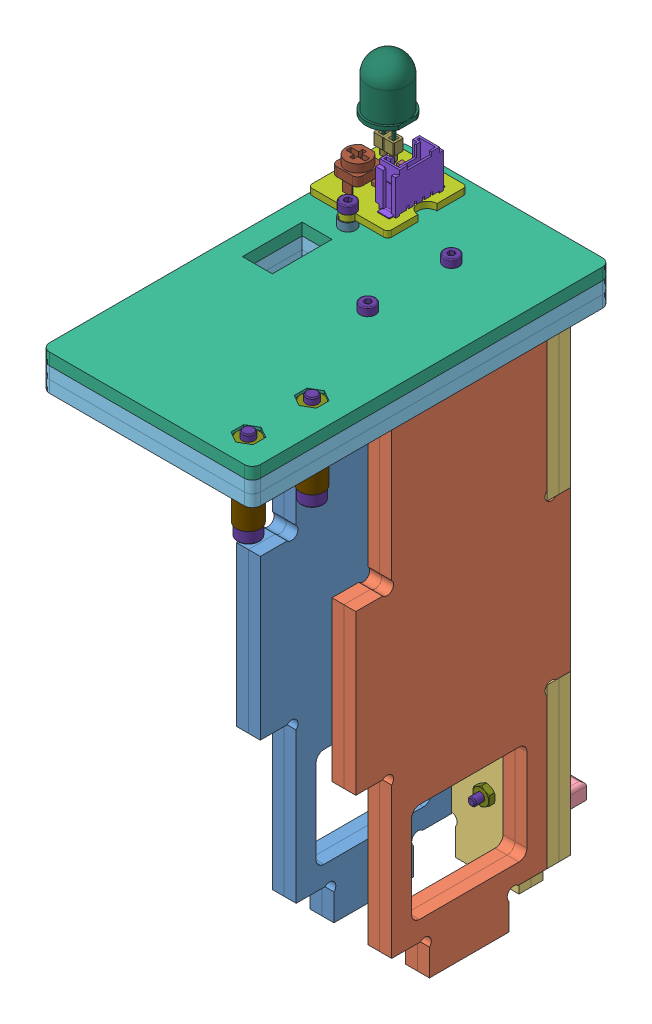
SolidWorks assembly pilier_droit, configuration Défaut. Lengths in mm.
Overall size (53 165.17 99).
42 component instances, 19 part files, 81 mates.
Components (placement in the parent):
- pilier-cote-2-1: pilier-cote-2 [Défaut] at (-45.8322 -68.3923 0) size (3 133 54)
- pilier-cote-3-2: pilier-cote-3 [Défaut] at (-18.8322 -68.3923 0) size (3 133 54)
- pilier-devant-1: pilier-devant [Défaut] at (-45.8322 -68.3923 -54) size (30 133 3)
- pilier-devant-2: pilier-devant [Défaut] at (-45.8322 -68.3923 -51) size (30 133 3)
- pilier-cote-2-3: pilier-cote-2 [Défaut] at (-42.8322 -68.3923 0) size (3 133 54)
- pilier-cote-3-4: pilier-cote-3 [Défaut] at (-21.8322 -68.3923 0) size (3 133 54)
- equerre-1: equerre [Défaut] at (-30.8322 -59.3923 -54) x (-1 0 0) z (0 0 -1) size (10 14 14)
- pilier_droit-chapeau-1-1: pilier_droit-chapeau-1 [Défaut] at (-63.8322 60.6077 31) size (53 3 90)
- pilier_droit-chapeau-1-2: pilier_droit-chapeau-1 [Défaut] at (-63.8322 63.6077 31) size (53 3 90)
- pilier_droit-chapeau-2-1: pilier_droit-chapeau-2 [Défaut] at (-63.8322 66.6077 31) size (53 3 90)
- Grove support LED-1: Grove support LED [Défaut] at (-59.2877 75.7919 -44) size (20 13.2 23.6)
  - PCB grove 20x20-1: PCB grove 20x20 [Défaut] at (7.4555 -4.1841 0) size (20 1.6 23.6)
  - Connecteur Grove (droit CMS)-1: Connecteur Grove (droit CMS) [Défaut] at (10.4555 -2.5841 0) x (-1 0 0) z (0 1 0) size (6.5 14 10)
  - 603 resistor 102-2: 603 resistor 102 [Default] at (3.6365 -2.5841 -1.49) size (2.36 0.62 1.03)
  - 603 cap on pad-1: 603 cap on pad [Défaut] at (8.4655 -2.5841 -6.62) x (0 0 1) z (-1 0 0) size (2.76 0.91 1.12)
  - 603 resistor 102-3: 603 resistor 102 [Default] at (6.6365 -2.5841 -1.49) size (2.36 0.62 1.03)
  - 603 resistor 102-4: 603 resistor 102 [Default] at (6.6365 -2.5841 -2.99) size (2.36 0.62 1.03)
  - Pot - RES_VAR1-1: Pot - RES_VAR1 [Défaut] at (4.0824 2.7159 4.0972) size (6.5 10.5 7.06)
  - Contact F-1: Contact F [Défaut] at (0.621 0.0871 -5.7728) size (2.54 7.5 2.54)
  - ssot3-1: ssot3 [Default] at (6.0932 -2.5841 -5.7439) size (3 1.13 3.09)
  - Contact F-2: Contact F [Défaut] at (3.161 0.0871 -5.7728) size (2.54 7.5 2.54)
- entretoise-grove-1: entretoise-grove [Défaut] at (-51.8322 71.6077 -34) x (1 0 0) z (0 -1 0) size (4 4 2)
- chapeau_pilier_droit-led_jaune-10-1: chapeau_pilier_droit-led_jaune-10 [Default] at (-57.5966 83.2789 -49.8228) x (1 0 0) z (0 1 0) size (10.5 11 23.5)
- entretoise-grove-2: entretoise-grove [Défaut] at (-51.8322 71.6077 -54) x (1 0 0) z (0 -1 0) size (4 4 2)
- ecrou-h-1: ecrou-h [6007 HU M2] at (-51.8322 60.6077 -54) x (0.5 0 0.866025) z (-0.866025 0 0.5) size (4 1.6 4.62)
- vis-chc-1: vis-chc [Vis CHC M2x16] at (-51.8322 73.2077 -54) x (0.657231 0 0.753689) z (-0.753689 0 0.657231) size (3.8 18 3.8)
- vis-chc-2: vis-chc [Vis CHC M2x16] at (-51.8322 73.2077 -34) x (0.657231 0 0.753689) z (-0.753689 0 0.657231) size (3.8 18 3.8)
- ecrou-h-2: ecrou-h [6007 HU M2] at (-51.8322 60.6077 -34) x (-0.866025 0 0.5) z (-0.5 0 -0.866025) size (4 1.6 4.62)
- vis-chc-3: vis-chc [Vis CHC M3x20] at (-18.8322 50.6077 24) x (-0.990761 0 0.135623) z (0.135623 0 0.990761) size (5.5 23 5.5)
- vis-chc-4: vis-chc [Vis CHC M3x20] at (-18.8322 50.6077 8) x (-0.990761 0 0.135623) z (0.135623 0 0.990761) size (5.5 23 5.5)
- ecrou-h-4: ecrou-h [6012 HU M3] at (-18.8322 69.0077 8) x (0.5 0 0.866025) z (-0.866025 0 0.5) size (5.5 2.4 6.35)
- ecrou-h-5: ecrou-h [6012 HU M3] at (-18.8322 69.0077 24) x (-0.5 0 0.866025) z (-0.866025 0 -0.5) size (5.5 2.4 6.35)
- ecrou-h-6: ecrou-h [6007 HU M2] at (-30.8322 51.6077 -46) x (-0.866025 0.5 0) z (-0.5 -0.866025 0) size (4 1.6 4.62)
- ecrou-h-7: ecrou-h [6007 HU M2] at (-30.8322 58.6077 -39) x (0 0 -1) z (1 0 0) size (4 1.6 4.62)
- vis-chc-5: vis-chc [Vis CHC M2x12] at (-30.8322 51.6077 -54) x (0.657231 0.753689 0) z (-0.753689 0.657231 0) size (3.8 14 3.8)
- vis-chc-6: vis-chc [Vis CHC M2x16] at (-30.8322 69.6077 -39) x (-0.137988 0 -0.990434) z (0.990434 0 -0.137988) size (3.8 18 3.8)
- vis-chc-7: vis-chc [Vis CHC M2x16] at (-30.8322 69.6077 -18) x (-0.137988 0 -0.990434) z (0.990434 0 -0.137988) size (3.8 18 3.8)
- grille-patin-1: grille-patin [Défaut] at (-18.8322 60.6077 8) x (0.804119 0 0.594469) z (0 -1 0) size (6 6 10)
- grille-patin-2: grille-patin [Défaut] at (-18.8322 60.6077 24) x (-0.010244 0 0.999948) z (0 -1 0) size (6 6 10)
- equerre-double_ecrou-2: equerre-double_ecrou [Défaut] at (-30.8322 60.6077 -48) x (-1 0 0) z (0 0 1) size (10 14 14)
- vis-chc-8: vis-chc [Vis CHC M2x12] at (-30.8322 -50.3923 -56) x (0.657231 0.753689 0) z (-0.753689 0.657231 0) size (3.8 14 3.8)
- ecrou-h-8: ecrou-h [6007 HU M2] at (-30.8322 -50.3923 -46.4) x (0.5 -0.866025 0) z (-0.866025 -0.5 0) size (4 1.6 4.62)
Mates (geometry in assembly coordinates):
- Coïncidente1: coincident aligned: plane of pilier-cote-2-1 through (-42.8322 60.6077 -40.7627) normal (0 1 0); plane of pilier-devant-1 through (-41.0949 60.6077 -51) normal (0 1 0)
- Coïncidente2: coincident aligned: plane of pilier-cote-2 through (-15.8322 60.6077 -40.7627) normal (0 1 0); plane of pilier-devant-1 through (-20.5694 60.6077 -51) normal (0 1 0)
- Coïncidente3: coincident aligned: plane of pilier-cote-2-1 through (-45.8322 -20.5236 -49.1314) normal (-1 0 0); plane of pilier-devant-1 through (-45.8322 20.6077 -51) normal (-1 0 0)
- Coïncidente4: coincident aligned: plane of pilier-cote-2-1 through (-42.8322 20.6077 -54) normal (0 0 -1); plane of pilier-devant-1 through (-21.7008 -60.5236 -54) normal (0 0 -1)
- Coïncidente5: coincident aligned: plane of pilier-cote-2 through (-15.8322 20.6077 -54) normal (0 0 -1); plane of pilier-devant-1 through (-21.7008 -60.5236 -54) normal (0 0 -1)
- Coïncidente6: coincident aligned: plane of pilier-cote-2 through (-15.8322 -20.5236 -49.1314) normal (1 0 0); plane of pilier-devant-1 through (-15.8322 20.6077 -51) normal (1 0 0)
- Coïncidente7: coincident anti-aligned: plane of pilier-devant-1 through (-21.7008 -60.5236 -51) normal (0 0 1); plane of pilier-devant-2 through (-21.7008 -60.5236 -51) normal (0 0 -1)
- Coïncidente8: coincident aligned: plane of pilier-devant-1 through (-38.8322 64.6077 -51) normal (0 1 0); plane of pilier-devant-2 through (-38.8322 64.6077 -48) normal (0 1 0)
- Coïncidente9: coincident aligned: plane of pilier-devant-1 through (-15.8322 20.6077 -51) normal (1 0 0); plane of pilier-devant-2 through (-15.8322 20.6077 -48) normal (1 0 0)
- Coïncidente11: coincident anti-aligned: plane of pilier-cote-2-1 through (-42.8322 -20.5236 -49.1314) normal (1 0 0); plane of pilier-cote-2-3 through (-42.8322 -20.5236 -49.1314) normal (-1 0 0)
- Coïncidente12: coincident aligned: plane of pilier-cote-2-1 through (-42.8322 64.6077 -18.5) normal (0 1 0); plane of pilier-cote-2-3 through (-39.8322 64.6077 -18.5) normal (0 1 0)
- Coïncidente13: coincident aligned: plane of pilier-cote-2-1 through (-42.8322 20.6077 -54) normal (0 0 -1); plane of pilier-cote-2-3 through (-39.8322 20.6077 -54) normal (0 0 -1)
- Coïncidente14: coincident anti-aligned: plane of pilier-cote-2 through (-18.8322 -20.5236 -49.1314) normal (-1 0 0); plane of pilier-cote-4 through (-18.8322 -20.5236 -49.1314) normal (1 0 0)
- Coïncidente15: coincident aligned: plane of pilier-cote-2 through (-15.8322 64.6077 -18.5) normal (0 1 0); plane of pilier-cote-4 through (-18.8322 64.6077 -18.5) normal (0 1 0)
- Coïncidente16: coincident: line of pilier-cote-2 through (-18.8322 22.8705 -48) axis (0 1 0); plane of pilier-cote-4 through (-18.8322 60.6077 -48) normal (0 0 -1)
- Coïncidente17: coincident anti-aligned: plane of pilier-devant-1 through (-21.7008 -60.5236 -54) normal (0 0 -1); plane of equerre-1 through (-30.8322 -59.3923 -54) normal (0 0 1)
- Coïncidente18: coincident aligned: plane of pilier-devant-1 through (-20.5694 -59.3923 -51) normal (0 -1 0); plane of equerre-1 through (-25.8322 -59.3923 -58) normal (0 -1 0)
- Coaxiale1: concentric anti-aligned: cylinder of pilier-devant-1 through (-30.8322 -50.3923 -54) axis (0 0 1) radius 1.1; cylinder of equerre-1 through (-30.8322 -50.3923 -54) axis (0 0 -1) radius 1.1
- Coïncidente19: coincident anti-aligned: plane of pilier-devant-2 through (-21.7008 -60.5236 -48) normal (0 0 1); plane of chapeau_pilier_droit-1 through (-25.0949 63.6077 -48) normal (0 0 -1)
- Coïncidente20: coincident anti-aligned: plane of pilier-devant-1 through (-38.8322 62.8705 -51) normal (-1 0 0); plane of chapeau_pilier_droit-1 through (-38.8322 63.6077 -51.7373) normal (1 0 0)
- Coïncidente21: coincident anti-aligned: plane of pilier-devant-1 through (-41.0949 60.6077 -51) normal (0 1 0); plane of chapeau_pilier_droit-1 through (-12.8322 60.6077 -57) normal (0 -1 0)
- Coïncidente22: coincident anti-aligned: plane of chapeau_pilier_droit-1 through (-12.8322 63.6077 -57) normal (0 1 0); plane of chapeau_pilier_droit-2 through (-12.8322 63.6077 -57) normal (0 -1 0)
- Coïncidente23: coincident aligned: plane of chapeau_pilier_droit-1 through (-63.8322 63.6077 -57) normal (-1 0 0); plane of chapeau_pilier_droit-2 through (-63.8322 66.6077 -57) normal (-1 0 0)
- Coïncidente24: coincident aligned: plane of chapeau_pilier_droit-1 through (-61.8322 63.6077 -59) normal (0 0 -1); plane of chapeau_pilier_droit-2 through (-61.8322 66.6077 -59) normal (0 0 -1)
- Coïncidente25: coincident anti-aligned: plane of chapeau_pilier_droit-2 through (-12.8322 66.6077 -57) normal (0 1 0); plane of pilier_droit-chapeau-2-1 through (-12.8322 66.6077 -57) normal (0 -1 0)
- Coïncidente26: coincident aligned: plane of chapeau_pilier_droit-2 through (-63.8322 66.6077 -57) normal (-1 0 0); plane of pilier_droit-chapeau-2-1 through (-63.8322 69.6077 -57) normal (-1 0 0)
- Coïncidente27: coincident aligned: plane of chapeau_pilier_droit-2 through (-61.8322 66.6077 -59) normal (0 0 -1); plane of pilier_droit-chapeau-2-1 through (-61.8322 69.6077 -59) normal (0 0 -1)
- Coaxiale2: concentric anti-aligned: cylinder of Grove support LED-1/PCB grove 20x20-1 through (-51.8322 73.2077 -34) axis (0 -1 0) radius 1.1; cylinder of entretoise-grove-1 through (-51.8322 69.6077 -34) axis (0 1 0) radius 1.2
- Distance1: distance = 5 mm: line of Grove support LED-1/Contact F-2 through (-55.8266 78.2789 -50.0728) axis (-1 0 0); line of chapeau_pilier_droit-led_jaune-10-1 through (-56.3266 73.2789 -50.0728) axis (1 0 0)
- Coaxiale3: concentric anti-aligned: cylinder of Grove support LED-1/PCB grove 20x20-1 through (-51.8322 73.2077 -54) axis (0 -1 0) radius 1.1; cylinder of entretoise-grove-2 through (-51.8322 69.6077 -54) axis (0 1 0) radius 1.2
- Coïncidente28: coincident anti-aligned: plane of Grove support LED-1/PCB grove 20x20-1 through (-51.8322 71.6077 -44) normal (0 -1 0); plane of entretoise-grove-1 through (-51.8322 71.6077 -34) normal (0 1 0)
- Coïncidente29: coincident anti-aligned: plane of Grove support LED-1/Contact F-2 through (-55.8266 78.6789 -49.4728) normal (-1 0 0); plane of chapeau_pilier_droit-led_jaune-10-1 through (-55.8266 83.2789 -50.0728) normal (1 0 0)
- Coïncidente30: coincident anti-aligned: plane of Grove support LED-1/Contact F-2 through (-56.4266 78.6789 -50.0728) normal (0 0 1); plane of chapeau_pilier_droit-led_jaune-10-1 through (-57.5966 83.2789 -50.0728) normal (0 0 -1)
- Coïncidente31: coincident anti-aligned: plane of Grove support LED-1/PCB grove 20x20-1 through (-51.8322 71.6077 -44) normal (0 -1 0); plane of entretoise-grove-2 through (-51.8322 71.6077 -54) normal (0 1 0)
- Coïncidente32: coincident anti-aligned: plane of pilier_droit-chapeau-2-1 through (-12.8322 69.6077 -57) normal (0 1 0); plane of entretoise-grove-2 through (-51.8322 69.6077 -54) normal (0 -1 0)
- Coaxiale4: concentric aligned: cylinder of pilier_droit-chapeau-2-1 through (-51.8322 66.6077 -54) axis (0 1 0) radius 1.1; cylinder of entretoise-grove-2 through (-51.8322 69.6077 -54) axis (0 1 0) radius 1.2
- Coaxiale5: concentric anti-aligned: cylinder of pilier_droit-chapeau-2-1 through (-51.8322 66.6077 -34) axis (0 1 0) radius 1.1; cylinder of Grove support LED-1/PCB grove 20x20-1 through (-51.8322 73.2077 -34) axis (0 -1 0) radius 1.1
- Coaxiale6: concentric anti-aligned: cylinder of Grove support LED-1/PCB grove 20x20-1 through (-51.8322 73.2077 -34) axis (0 -1 0) radius 1.1; cylinder of vis-chc-2 through (-51.8322 57.2077 -34) axis (0 1 0) radius 1
- Coaxiale7: concentric anti-aligned: cylinder of Grove support LED-1/PCB grove 20x20-1 through (-51.8322 73.2077 -54) axis (0 -1 0) radius 1.1; cylinder of vis-chc-1 through (-51.8322 57.2077 -54) axis (0 1 0) radius 1
- Coïncidente33: coincident anti-aligned: plane of Grove support LED-1/PCB grove 20x20-1 through (-51.8322 73.2077 -44) normal (0 1 0); plane of vis-chc-2 through (-51.8322 73.2077 -34) normal (0 -1 0)
- Coïncidente34: coincident anti-aligned: plane of Grove support LED-1/PCB grove 20x20-1 through (-51.8322 73.2077 -44) normal (0 1 0); plane of vis-chc-1 through (-51.8322 73.2077 -54) normal (0 -1 0)
- Coïncidente35: coincident anti-aligned: plane of chapeau_pilier_droit-1 through (-12.8322 60.6077 -57) normal (0 -1 0); plane of ecrou-h-1 through (-49.8322 60.6077 -52.8453) normal (0 1 0)
- Coaxiale8: concentric aligned: cylinder of ecrou-h-1 through (-51.8322 59.0077 -54) axis (0 1 0) radius 0.7835; cylinder of vis-chc-1 through (-51.8322 57.2077 -54) axis (0 1 0) radius 1
- Parallèle1: parallel aligned: plane of chapeau_pilier_droit-1 through (-63.8322 63.6077 -57) normal (-1 0 0); plane of ecrou-h-1 through (-53.8322 59.0077 -55.1547) normal (-1 0 0)
- Coïncidente37: coincident anti-aligned: plane of chapeau_pilier_droit-1 through (-12.8322 60.6077 -57) normal (0 -1 0); plane of ecrou-h-2 through (-52.9869 60.6077 -32) normal (0 1 0)
- Coaxiale9: concentric aligned: cylinder of vis-chc-2 through (-51.8322 57.2077 -34) axis (0 1 0) radius 1; cylinder of ecrou-h-2 through (-51.8322 59.0077 -34) axis (0 1 0) radius 0.7835
- Parallèle2: parallel aligned: plane of chapeau_pilier_droit-1 through (-61.8322 63.6077 -59) normal (0 0 -1); plane of ecrou-h-2 through (-50.6775 59.0077 -36) normal (0 0 -1)
- Coaxiale10: concentric anti-aligned: cylinder of chapeau_pilier_droit-1 through (-18.8322 63.6077 24) axis (0 -1 0) radius 1.6; cylinder of entretoise-6x10-2 through (-18.8322 50.6077 24) axis (0 1 0) radius 2
- Coaxiale11: concentric anti-aligned: cylinder of chapeau_pilier_droit-1 through (-18.8322 63.6077 8) axis (0 -1 0) radius 1.6; cylinder of entretoise-6x10-1 through (-18.8322 50.6077 8) axis (0 1 0) radius 2
- Coïncidente39: coincident anti-aligned: plane of chapeau_pilier_droit-1 through (-12.8322 60.6077 -57) normal (0 -1 0); plane of entretoise-6x10-2 through (-18.8322 60.6077 24) normal (0 1 0)
- Coïncidente40: coincident anti-aligned: plane of chapeau_pilier_droit-1 through (-12.8322 60.6077 -57) normal (0 -1 0); plane of entretoise-6x10-1 through (-18.8322 60.6077 8) normal (0 1 0)
- Coaxiale12: concentric anti-aligned: cylinder of entretoise-6x10-2 through (-18.8322 50.6077 24) axis (0 1 0) radius 2; cylinder of vis-chc-3 through (-18.8322 70.6077 24) axis (0 -1 0) radius 1.5
- Coïncidente41: coincident anti-aligned: plane of entretoise-6x10-2 through (-18.8322 50.6077 24) normal (0 -1 0); plane of vis-chc-3 through (-18.8322 50.6077 24) normal (0 1 0)
- Coaxiale13: concentric anti-aligned: cylinder of entretoise-6x10-1 through (-18.8322 50.6077 8) axis (0 1 0) radius 2; cylinder of vis-chc-4 through (-18.8322 70.6077 8) axis (0 -1 0) radius 1.5
- Coïncidente42: coincident anti-aligned: plane of entretoise-6x10-1 through (-18.8322 50.6077 8) normal (0 -1 0); plane of vis-chc-4 through (-18.8322 50.6077 8) normal (0 1 0)
- Coaxiale14: concentric anti-aligned: cylinder of vis-chc-4 through (-18.8322 70.6077 8) axis (0 -1 0) radius 1.5; cylinder of ecrou-h-4 through (-18.8322 66.6077 8) axis (0 1 0) radius 1.2295
- Parallèle3: parallel anti-aligned: plane of pilier_droit-chapeau-2-1 through (-21.8633 66.6077 6.3471) normal (1 0 0); plane of ecrou-h-4 through (-21.5822 66.6077 6.4123) normal (-1 0 0)
- Coaxiale15: concentric anti-aligned: cylinder of vis-chc-3 through (-18.8322 70.6077 24) axis (0 -1 0) radius 1.5; cylinder of ecrou-h-5 through (-18.8322 66.6077 24) axis (0 1 0) radius 1.2295
- Parallèle4: parallel anti-aligned: plane of pilier_droit-chapeau-2-1 through (-21.8633 66.6077 22.25) normal (1 0 0); plane of ecrou-h-5 through (-21.5822 66.6077 22.4123) normal (-1 0 0)
- Coïncidente45: coincident anti-aligned: plane of chapeau_pilier_droit-2 through (-12.8322 66.6077 -57) normal (0 1 0); plane of ecrou-h-5 through (-18.8322 66.6077 27.1754) normal (0 -1 0)
- Coïncidente46: coincident anti-aligned: plane of chapeau_pilier_droit-2 through (-12.8322 66.6077 -57) normal (0 1 0); plane of ecrou-h-4 through (-16.0822 66.6077 9.5877) normal (0 -1 0)
- Coaxiale16: concentric aligned: cylinder of pilier-devant-2 through (-30.8322 51.6077 -51) axis (0 0 1) radius 1.1; cylinder of equerre-double_ecrou-2 through (-30.8322 51.6077 -48) axis (0 0 1) radius 1.1
- Coïncidente47: coincident anti-aligned: plane of pilier-devant-2 through (-21.7008 -60.5236 -48) normal (0 0 1); plane of equerre-double_ecrou-2 through (-30.8322 60.6077 -48) normal (0 0 -1)
- Coïncidente48: coincident anti-aligned: plane of chapeau_pilier_droit-1 through (-12.8322 60.6077 -57) normal (0 -1 0); plane of equerre-double_ecrou-2 through (-25.8322 60.6077 -44) normal (0 1 0)
- Coaxiale17: concentric anti-aligned: cylinder of equerre-double_ecrou-2 through (-30.8322 51.6077 -48) axis (0 0 1) radius 1.1; cylinder of ecrou-h-6 through (-30.8322 51.6077 -44.4) axis (0 0 -1) radius 0.7835
- Parallèle5: parallel anti-aligned: plane of equerre-double_ecrou-2 through (-29.5822 49.4427 -46) normal (-0.866025 0.5 0); plane of ecrou-h-6 through (-28.5228 51.6077 -44.4) normal (0.866025 -0.5 0)
- Coïncidente51: coincident anti-aligned: plane of equerre-double_ecrou-2 through (-30.8322 60.6077 -46) normal (0 0 1); plane of ecrou-h-6 through (-31.9869 53.6077 -46) normal (0 0 -1)
- Coaxiale18: concentric anti-aligned: cylinder of equerre-double_ecrou-2 through (-30.8322 60.6077 -39) axis (0 -1 0) radius 1.1; cylinder of ecrou-h-7 through (-30.8322 57.0077 -39) axis (0 1 0) radius 0.7835
- Parallèle6: parallel anti-aligned: plane of equerre-double_ecrou-2 through (-32.0822 58.6077 -41.1651) normal (0 0 1); plane of ecrou-h-7 through (-29.6775 57.0077 -41) normal (0 0 -1)
- Coïncidente53: coincident anti-aligned: plane of equerre-double_ecrou-2 through (-30.8322 58.6077 -48) normal (0 -1 0); plane of ecrou-h-7 through (-31.9869 58.6077 -41) normal (0 1 0)
- Coaxiale19: concentric anti-aligned: cylinder of pilier-devant-1 through (-30.8322 51.6077 -54) axis (0 0 1) radius 1.1; cylinder of vis-chc-5 through (-30.8322 51.6077 -42) axis (0 0 -1) radius 1
- Coïncidente54: coincident anti-aligned: plane of pilier-devant-1 through (-21.7008 -60.5236 -54) normal (0 0 -1); plane of vis-chc-5 through (-30.8322 51.6077 -54) normal (0 0 1)
- Coaxiale20: concentric aligned: cylinder of pilier_droit-chapeau-2-1 through (-30.8322 66.6077 -39) axis (0 1 0) radius 1.1; cylinder of vis-chc-6 through (-30.8322 53.6077 -39) axis (0 1 0) radius 1
- Coïncidente55: coincident anti-aligned: plane of pilier_droit-chapeau-2-1 through (-12.8322 69.6077 -57) normal (0 1 0); plane of vis-chc-6 through (-30.8322 69.6077 -39) normal (0 -1 0)
- Coaxiale21: concentric aligned: cylinder of pilier_droit-chapeau-2-1 through (-30.8322 66.6077 -18) axis (0 1 0) radius 1.1; cylinder of vis-chc-7 through (-30.8322 53.6077 -18) axis (0 1 0) radius 1
- Coïncidente56: coincident anti-aligned: plane of pilier_droit-chapeau-2-1 through (-12.8322 69.6077 -57) normal (0 1 0); plane of vis-chc-7 through (-30.8322 69.6077 -18) normal (0 -1 0)
- Coaxiale22: concentric aligned: cylinder of equerre-1 through (-30.8322 -50.3923 -54) axis (0 0 -1) radius 1.1; cylinder of vis-chc-8 through (-30.8322 -50.3923 -44) axis (0 0 -1) radius 1
- Coïncidente57: coincident anti-aligned: plane of equerre-1 through (-30.8322 -50.3923 -56) normal (0 0 -1); plane of vis-chc-8 through (-30.8322 -50.3923 -56) normal (0 0 1)
- Coaxiale23: concentric anti-aligned: cylinder of vis-chc-8 through (-30.8322 -50.3923 -44) axis (0 0 -1) radius 1; cylinder of ecrou-h-8 through (-30.8322 -50.3923 -48) axis (0 0 1) radius 0.7835
- Coïncidente58: coincident anti-aligned: plane of pilier-devant-2 through (-21.7008 -60.5236 -48) normal (0 0 1); plane of ecrou-h-8 through (-28.8322 -51.547 -48) normal (0 0 -1)
- Parallèle7: parallel aligned: plane of pilier-devant-2 through (-45.8322 -19.3923 -48) normal (-1 0 0); plane of ecrou-h-8 through (-32.8322 -49.2375 -48) normal (-1 0 0)
